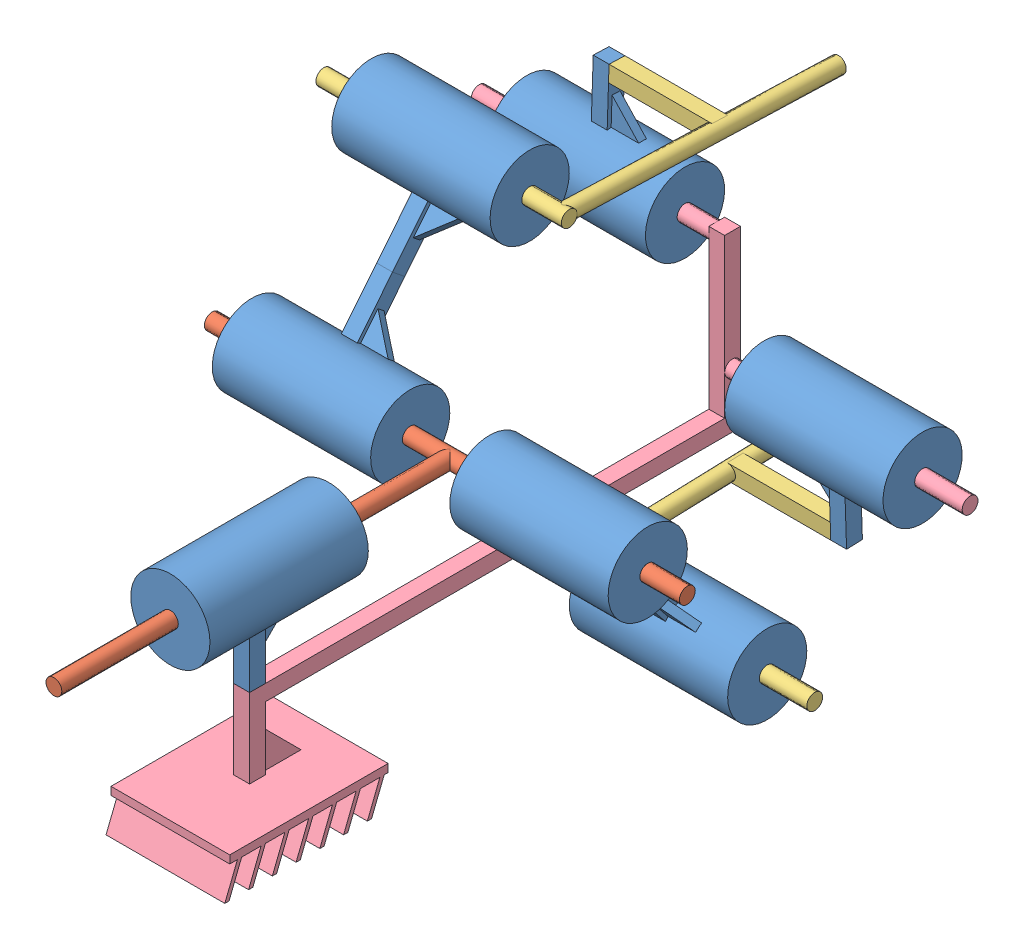
SolidWorks assembly pince-cinematique, configuration Défaut. Lengths in mm.
Overall size (62 52.7 100.1).
11 component instances, 4 part files, 29 mates.
Components (placement in the parent):
- portee_verte-1: portee_verte [Défaut] at (-4.8439 3.3152 0) size (10 17 20)
- portee_verte-2: portee_verte [Défaut] at (-19.8439 3.3152 -25.2918) x (0 -0.628671 -0.777671) z (-1 0 0) size (10 17 20)
- axe_jaune-piston-1: axe_jaune-piston [Défaut] at (-4.8439 3.3152 -25.2918) x (0 1 0) z (0 0 -1) size (2 60 51)
- portee_verte-3: portee_verte [Défaut] at (10.1561 3.3152 -25.2918) x (0 -0.628671 0.777671) z (-1 0 0) size (10 17 20)
- portee_verte-4: portee_verte [Défaut] at (-19.8439 21.9793 -40.3799) x (0 0.628671 0.777671) z (-1 0 0) size (10 17 20)
- portee_verte-5: portee_verte [Défaut] at (10.1561 -15.3489 -40.3799) x (0 0.628671 -0.777671) z (-1 0 0) size (10 17 20)
- axe-bielette-1: axe-bielette [Défaut] at (-3.8439 -15.3489 -40.3799) x (0 -0.999438 -0.033514) z (0 -0.033514 0.999438) size (2 31 36)
- axe-bielette-2: axe-bielette [Défaut] at (-5.8439 21.9793 -40.3799) x (0 0.999438 -0.033514) z (0 0.033514 0.999438) size (2 31 36)
- fixe-corps-1: fixe-corps [Défaut] at (-4.8439 -19.6848 0) size (62 35 71.62)
- portee_verte-6: portee_verte [Défaut] at (-19.8439 10.3152 -60) x (0 -0.033514 -0.999438) z (-1 0 0) size (10 17 20)
- portee_verte-7: portee_verte [Défaut] at (10.1561 -3.6848 -60) x (0 0.033514 -0.999438) z (1 0 0) size (10 17 20)
Mates (geometry in assembly coordinates):
- Coaxiale1: concentric anti-aligned: cylinder of portee_verte-1 through (-4.8439 3.3152 -10) axis (0 0 1) radius 1; cylinder of axe_jaune-piston-1 through (-4.8439 3.3152 24.7082) axis (0 0 -1) radius 1
- Coaxiale2: concentric anti-aligned: cylinder of portee_verte-2 through (-9.8439 3.3152 -25.2918) axis (-1 0 0) radius 1; cylinder of axe_jaune-piston-1 through (-34.8439 3.3152 -25.2918) axis (1 0 0) radius 1
- Parallèle1: parallel aligned: plane of portee_verte-1 through (-3.8439 -8.6848 1) normal (1 0 0); plane of axe_jaune-piston-1 through (25.1561 3.3152 -25.2918) normal (1 0 0)
- Distance1: distance = 5.7712 mm aligned: plane of axe_jaune-piston-1 through (-4.8439 3.3152 15.7712) normal (0 0 1); plane of portee_verte-1 through (-4.8439 3.3152 10) normal (0 0 1)
- Coaxiale3: concentric anti-aligned: cylinder of axe_jaune-piston-1 through (-34.8439 3.3152 -25.2918) axis (1 0 0) radius 1; cylinder of portee_verte-3 through (20.1561 3.3152 -25.2918) axis (-1 0 0) radius 1
- Coïncidente6: coincident anti-aligned: plane of portee_verte-3 through (11.1561 -5.3882 -33.6135) normal (0 -0.777671 -0.628671); plane of portee_verte-5 through (11.1561 -6.6455 -32.0582) normal (0 0.777671 0.628671)
- Coïncidente7: coincident aligned: plane of portee_verte-3 through (11.1561 -6.6455 -32.0582) normal (1 0 0); plane of portee_verte-5 through (11.1561 -5.3882 -33.6135) normal (1 0 0)
- Coïncidente8: coincident aligned: plane of portee_verte-3 through (9.1561 -5.3882 -33.6135) normal (0 0.628671 -0.777671); plane of portee_verte-5 through (9.1561 -5.3882 -33.6135) normal (0 0.628671 -0.777671)
- Coïncidente9: coincident anti-aligned: plane of portee_verte-2 through (-18.8439 13.2759 -32.0582) normal (0 0.777671 -0.628671); plane of portee_verte-4 through (-18.8439 12.0186 -33.6135) normal (0 -0.777671 0.628671)
- Coïncidente10: coincident aligned: plane of portee_verte-2 through (-18.8439 12.0186 -33.6135) normal (1 0 0); plane of portee_verte-4 through (-18.8439 13.2759 -32.0582) normal (1 0 0)
- Coïncidente11: coincident aligned: plane of portee_verte-2 through (-20.8439 13.2759 -32.0582) normal (0 0.628671 0.777671); plane of portee_verte-4 through (-20.8439 13.2759 -32.0582) normal (0 0.628671 0.777671)
- Coaxiale4: concentric anti-aligned: cylinder of portee_verte-5 through (20.1561 -15.3489 -40.3799) axis (-1 0 0) radius 1; cylinder of axe-bielette-1 through (-4.8439 -15.3489 -40.3799) axis (1 0 0) radius 1
- Coaxiale5: concentric aligned: cylinder of portee_verte-4 through (-9.8439 21.9793 -40.3799) axis (-1 0 0) radius 1; cylinder of axe-bielette-2 through (-4.8439 21.9793 -40.3799) axis (-1 0 0) radius 1
- Coïncidente12: coincident anti-aligned: plane of portee_verte-1 through (-5.8439 -8.6848 -1) normal (0 -1 0); plane of fixe-corps-1 through (-5.8439 -8.6848 -1) normal (0 1 0)
- Coïncidente13: coincident aligned: plane of portee_verte-1 through (-3.8439 -8.6848 1) normal (1 0 0); plane of fixe-corps-1 through (-3.8439 -18.6848 -1) normal (1 0 0)
- Coïncidente14: coincident aligned: plane of portee_verte-1 through (-3.8439 -8.6848 1) normal (0 0 1); plane of fixe-corps-1 through (-5.8439 -8.6848 1) normal (0 0 1)
- Distance2: distance = 5 mm aligned: plane of axe-bielette-2 through (-4.8439 21.9793 -40.3799) normal (1 0 0); plane of portee_verte-4 through (-9.8439 21.9793 -40.3799) normal (1 0 0)
- Distance3: distance = 5 mm aligned: plane of axe_jaune-piston-1 through (-34.8439 3.3152 -25.2918) normal (-1 0 0); plane of portee_verte-2 through (-29.8439 3.3152 -25.2918) normal (-1 0 0)
- Distance4: distance = 5 mm aligned: plane of portee_verte-3 through (20.1561 3.3152 -25.2918) normal (1 0 0); plane of axe_jaune-piston-1 through (25.1561 3.3152 -25.2918) normal (1 0 0)
- Distance5: distance = 5 mm aligned: plane of axe_jaune-piston-1 through (-4.8439 3.3152 15) normal (0 0 1); plane of portee_verte-1 through (-4.8439 3.3152 10) normal (0 0 1)
- Distance6: distance = 5 mm aligned: plane of axe-bielette-1 through (-4.8439 -15.3489 -40.3799) normal (-1 0 0); plane of portee_verte-5 through (0.1561 -15.3489 -40.3799) normal (-1 0 0)
- Coïncidente20: coincident anti-aligned: cylinder of fixe-corps-1 through (-35.8439 10.3152 -60) axis (1 0 0) radius 1; circle of portee_verte-6
- Coïncidente21: coincident anti-aligned: cylinder of fixe-corps-1 through (26.1561 -3.6848 -60) axis (-1 0 0) radius 1; circle of portee_verte-7
- Coïncidente23: coincident aligned: plane of axe-bielette-2 through (-18.8439 22.275 -61.4016) normal (0 -0.033514 -0.999438); plane of portee_verte-6 through (-20.8439 22.275 -61.4016) normal (0 -0.033514 -0.999438)
- Coïncidente24: coincident aligned: plane of axe-bielette-2 through (-18.8439 22.275 -61.4016) normal (0 0.999438 -0.033514); plane of portee_verte-6 through (-18.8439 22.342 -59.4027) normal (0 0.999438 -0.033514)
- Coïncidente25: coincident aligned: plane of axe-bielette-1 through (9.1561 -15.6445 -61.4016) normal (0 -0.999438 -0.033514); plane of portee_verte-7 through (9.1561 -15.7116 -59.4027) normal (0 -0.999438 -0.033514)
- Coïncidente26: coincident aligned: plane of axe-bielette-1 through (9.1561 -15.6445 -61.4016) normal (0 0.033514 -0.999438); plane of portee_verte-7 through (11.1561 -15.6445 -61.4016) normal (0 0.033514 -0.999438)
- Coïncidente29: coincident anti-aligned: plane of axe-bielette-1 through (9.1561 -15.7116 -59.4027) normal (1 0 0); plane of portee_verte-7 through (9.1561 -15.6445 -61.4016) normal (-1 0 0)
- Coïncidente30: coincident anti-aligned: plane of axe-bielette-2 through (-18.8439 22.342 -59.4027) normal (-1 0 0); plane of portee_verte-6 through (-18.8439 22.275 -61.4016) normal (1 0 0)
